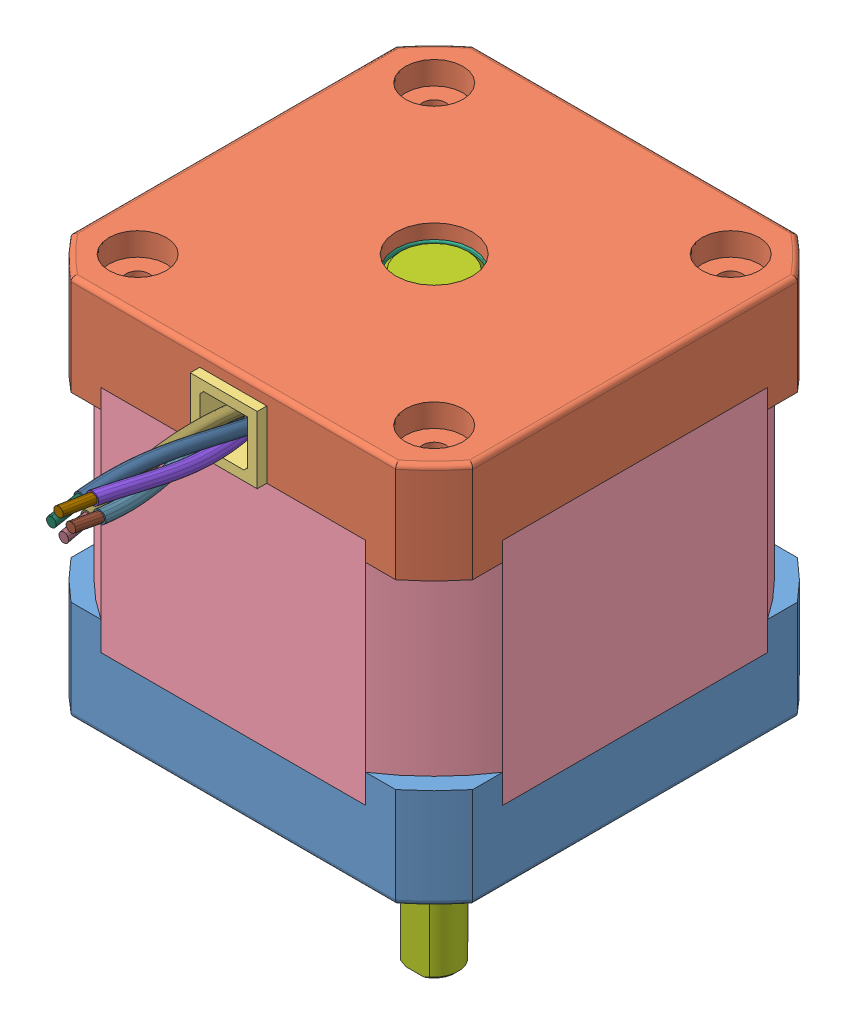
SolidWorks assembly NEMA17 x 40, configuration Predeterminado. Lengths in mm.
Overall size (42 64 60).
20 component instances, 19 part files, 0 mates.
Components (placement in the parent):
- NEMA17 x 40.step-1: NEMA17 x 40.step [Predeterminado] at origin size (42 64 60)
  - Frontplate.step-1: Frontplate.step [Predeterminado] at (0 10.5 0) size (42 12.5 42)
  - Backplate.step-1: Backplate.step [Predeterminado] at (0 40 0) size (42 10.5 42)
  - Connenctor.step-1: Connenctor.step [Predeterminado] at (0 31.5 22) size (7 7 7)
  - Housing.step-1: Housing.step [Predeterminado] at (0 7.5 0) size (42 24 42)
  - Bearing dummy.step-1: Bearing dummy.step [Predeterminado] at (0 4 0) size (22 7 22)
  - Bearing dummy 01.step-1: Bearing dummy 01.step [Predeterminado] at (0 35 0) size (22 7 22)
  - Core.step-1: Core.step [Predeterminado] at origin size (30 62.5 30)
  - M3x34-Screw.step-1: M3x34-Screw.step [Predeterminado] at (15.5 37.6 15.5) x (1 0 0) z (0 1 0) size (5.5 5.5 36) (hidden)
  - M3x34-Screw001.step-1: M3x34-Screw001.step [Predeterminado] at (-15.5 37.6 15.5) x (1 0 0) z (0 1 0) size (5.5 5.5 36) (hidden)
  - M3x34-Screw002.step-1: M3x34-Screw002.step [Predeterminado] at (-15.5 37.6 -15.5) x (1 0 0) z (0 1 0) size (5.5 5.5 36) (hidden)
  - M3x34-Screw003.step-1: M3x34-Screw003.step [Predeterminado] at (15.5 37.6 -15.5) x (1 0 0) z (0 1 0) size (5.5 5.5 36) (hidden)
  - Cable-1of4.step-1: Cable-1of4.step [Predeterminado] at (0 35 0) size (3.44 3.69 21)
  - Copper-1of4.step-1: Copper-1of4.step [Predeterminado] at (0 35 0) size (2.77 3.05 24)
  - Cable-2of4.step-1: Cable-2of4.step [Predeterminado] at (0 35 0) x (0 1 0) z (0 0 1) size (3.44 3.69 21)
  - Copper-4of4.step-1: Copper-4of4.step [Predeterminado] at (0 35 0) x (0 -1 0) z (0 0 1) size (2.77 3.05 24)
  - Cable-3of4.step-1: Cable-3of4.step [Predeterminado] at (0 35 0) x (-1 0 0) z (0 0 1) size (3.44 3.69 21)
  - Copper-3of4.step-1: Copper-3of4.step [Predeterminado] at (0 35 0) x (-1 0 0) z (0 0 1) size (2.77 3.05 24)
  - Cable-4of4.step-1: Cable-4of4.step [Predeterminado] at (0 35 0) x (0 -1 0) z (0 0 1) size (3.44 3.69 21)
  - Copper-2of4.step-1: Copper-2of4.step [Predeterminado] at (0 35 0) x (0 1 0) z (0 0 1) size (2.77 3.05 24)
